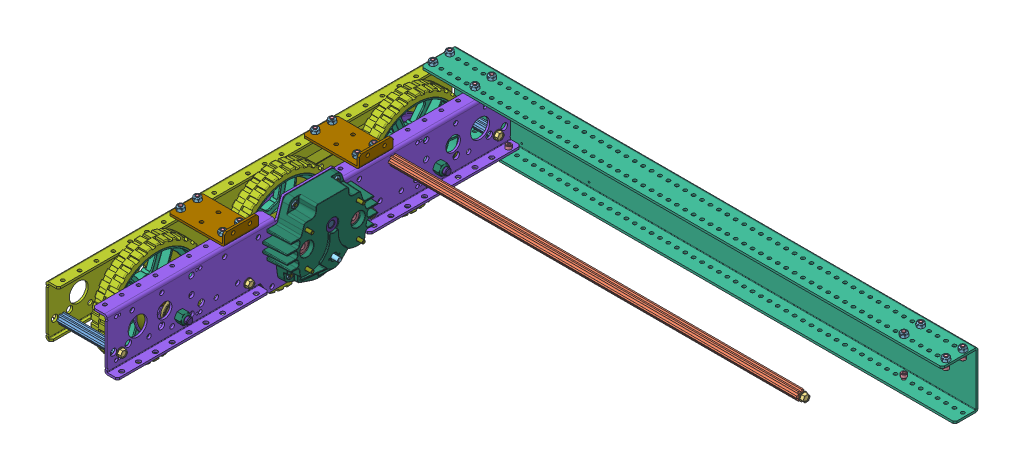
SolidWorks assembly AM14U3 Wide Half, configuration Default. Lengths in mm.
Overall size (799.92 215.23 613.54).
150 component instances, 35 part files, 25 mates.
Components (placement in the parent):
- AM14U3 Wide Frame Half-1: AM14U3 Wide Frame Half [Default] at (332.649 29.2384 -211.4076) size (799.34 116.33 613.54)
  - 500 Churro 3.375 in-1: 500 Churro 3.375 in [Default] at (-704.85 -61.341 539.242) x (0 0 1) z (-1 0 0) size (14.66 12.7 85.72)
  - 500 Churro 3.375 in-2: 500 Churro 3.375 in [Default] at (-704.85 -66.929 346.837) x (0 0 1) z (-1 0 0) size (14.66 12.7 85.72)
  - 500 Churro 3.375 in-3: 500 Churro 3.375 in [Default] at (-704.85 -66.929 162.687) x (0 0 1) z (-1 0 0) size (14.66 12.7 85.72)
  - 500 Churro 3.375 in-4: 500 Churro 3.375 in [Default] at (-790.575 -61.341 -29.718) x (0 0 -1) z (1 0 0) size (14.66 12.7 85.72)
  - 500 Churro 24.25 in-1: 500 Churro 24.25 in [Default] at (-85.725 -15.494 127.762) x (0 0 1) z (-1 0 0) size (14.66 12.7 615.95)
  - 0.25-20 x 0.75 in Thread Rolling Screw-1: 0.25-20 x 0.75 in Thread Rolling Screw [FHTS 0.25-20-G-0.75-C] at (-701.675 -61.341 539.242) x (-1 0 0) z (0 0.924225 0.381849) size (24.64 12.19 12.19)
  - 0.25-20 x 0.75 in Thread Rolling Screw-2: 0.25-20 x 0.75 in Thread Rolling Screw [FHTS 0.25-20-G-0.75-C] at (-701.675 -66.929 346.837) x (-1 0 0) z (0 0.924225 0.381849) size (24.64 12.19 12.19)
  - 0.25-20 x 0.75 in Thread Rolling Screw-3: 0.25-20 x 0.75 in Thread Rolling Screw [FHTS 0.25-20-G-0.75-C] at (-701.675 -66.929 162.687) x (-1 0 0) z (0 0.924225 0.381849) size (24.64 12.19 12.19)
  - 0.25-20 x 0.75 in Thread Rolling Screw-4: 0.25-20 x 0.75 in Thread Rolling Screw [FHTS 0.25-20-G-0.75-C] at (-701.675 -61.341 -29.718) x (-1 0 0) z (0 0.924225 0.381849) size (24.64 12.19 12.19)
  - 0.25-20 x 0.75 in Thread Rolling Screw-5: 0.25-20 x 0.75 in Thread Rolling Screw [FHTS 0.25-20-G-0.75-C] at (-793.75 -61.341 -29.718) size (24.64 12.19 12.19)
  - 0.25-20 x 0.75 in Thread Rolling Screw-6: 0.25-20 x 0.75 in Thread Rolling Screw [FHTS 0.25-20-G-0.75-C] at (-793.75 -66.929 162.687) size (24.64 12.19 12.19)
  - 0.25-20 x 0.75 in Thread Rolling Screw-7: 0.25-20 x 0.75 in Thread Rolling Screw [FHTS 0.25-20-G-0.75-C] at (-704.85 -15.494 127.762) size (24.64 12.19 12.19)
  - 0.25-20 x 0.75 in Thread Rolling Screw-8: 0.25-20 x 0.75 in Thread Rolling Screw [FHTS 0.25-20-G-0.75-C] at (-793.75 -66.929 346.837) size (24.64 12.19 12.19)
  - 0.25-20 x 0.75 in Thread Rolling Screw-9: 0.25-20 x 0.75 in Thread Rolling Screw [FHTS 0.25-20-G-0.75-C] at (-793.75 -61.341 539.242) size (24.64 12.19 12.19)
  - 0.25-20 x 0.75 in Thread Rolling Screw-10: 0.25-20 x 0.75 in Thread Rolling Screw [FHTS 0.25-20-G-0.75-C] at (-82.55 -15.494 127.762) x (-1 0 0) z (0 0.116139 -0.993233) size (24.64 12.19 12.19)
  - 10-32 x 0.5 in SHCS Screw-19: 10-32 x 0.5 in SHCS Screw [HX-SHCS 0.19-32x1.375x1-C] at (-781.05 -11.43 -37.338) x (0 1 0) z (0 0 1) size (17.53 7.94 7.94)
  - 10-32 x 0.5 in SHCS Screw-20: 10-32 x 0.5 in SHCS Screw [HX-SHCS 0.19-32x1.375x1-C] at (-781.05 -11.43 -11.938) x (0 1 0) z (0 0 1) size (17.53 7.94 7.94)
  - 10-32 x 0.5 in SHCS Screw-21: 10-32 x 0.5 in SHCS Screw [HX-SHCS 0.19-32x1.375x1-C] at (-717.55 -11.43 -37.338) x (0 1 0) z (0 0 1) size (17.53 7.94 7.94)
  - 10-32 x 0.5 in SHCS Screw-22: 10-32 x 0.5 in SHCS Screw [HX-SHCS 0.19-32x1.375x1-C] at (-717.55 -11.43 -11.938) x (0 1 0) z (0 0 1) size (17.53 7.94 7.94)
  - 10-32 x 0.5 in SHCS Screw-23: 10-32 x 0.5 in SHCS Screw [HX-SHCS 0.19-32x1.375x1-C] at (-781.05 -11.43 140.462) x (0 1 0) z (0 0 1) size (17.53 7.94 7.94)
  - 10-32 x 0.5 in SHCS Screw-24: 10-32 x 0.5 in SHCS Screw [HX-SHCS 0.19-32x1.375x1-C] at (-781.05 -11.43 165.862) x (0 1 0) z (0 0 1) size (17.53 7.94 7.94)
  - 10-32 x 0.5 in SHCS Screw-25: 10-32 x 0.5 in SHCS Screw [HX-SHCS 0.19-32x1.375x1-C] at (-717.55 -11.43 140.462) x (0 1 0) z (0 0 1) size (17.53 7.94 7.94)
  - 10-32 x 0.5 in SHCS Screw-26: 10-32 x 0.5 in SHCS Screw [HX-SHCS 0.19-32x1.375x1-C] at (-717.55 -11.43 165.862) x (0 1 0) z (0 0 1) size (17.53 7.94 7.94)
  - 10-32 x 0.5 in SHCS Screw-27: 10-32 x 0.5 in SHCS Screw [HX-SHCS 0.19-32x1.375x1-C] at (-781.05 -11.43 343.662) x (0 1 0) z (0 0 1) size (17.53 7.94 7.94)
  - 10-32 x 0.5 in SHCS Screw-28: 10-32 x 0.5 in SHCS Screw [HX-SHCS 0.19-32x1.375x1-C] at (-781.05 -11.43 369.062) x (0 1 0) z (0 0 1) size (17.53 7.94 7.94)
  - 10-32 x 0.5 in SHCS Screw-29: 10-32 x 0.5 in SHCS Screw [HX-SHCS 0.19-32x1.375x1-C] at (-717.55 -11.43 343.662) x (0 1 0) z (0 0 1) size (17.53 7.94 7.94)
  - 10-32 x 0.5 in SHCS Screw-30: 10-32 x 0.5 in SHCS Screw [HX-SHCS 0.19-32x1.375x1-C] at (-717.55 -11.43 369.062) x (0 1 0) z (0 0 1) size (17.53 7.94 7.94)
  - 10-32 x 0.5 in SHCS Screw-31: 10-32 x 0.5 in SHCS Screw [HX-SHCS 0.19-32x1.375x1-C] at (-692.15 -73.152 -37.338) x (0 -1 0) z (0 0 1) size (17.53 7.94 7.94)
  - 10-32 x 0.5 in SHCS Screw-32: 10-32 x 0.5 in SHCS Screw [HX-SHCS 0.19-32x1.375x1-C] at (-6.35 -11.176 -11.938) x (0 1 0) z (-0.461963 0 0.886899) size (17.53 7.94 7.94)
  - 10-32 x 0.5 in SHCS Screw-33: 10-32 x 0.5 in SHCS Screw [HX-SHCS 0.19-32x1.375x1-C] at (-6.35 -11.176 -37.338) x (0 1 0) z (0 0 1) size (17.53 7.94 7.94)
  - 10-32 x 0.5 in SHCS Screw-34: 10-32 x 0.5 in SHCS Screw [HX-SHCS 0.19-32x1.375x1-C] at (-69.85 -11.176 -11.938) x (0 1 0) z (0 0 1) size (17.53 7.94 7.94)
  - 10-32 x 0.5 in SHCS Screw-35: 10-32 x 0.5 in SHCS Screw [HX-SHCS 0.19-32x1.375x1-C] at (-69.85 -11.176 -37.338) x (0 1 0) z (0 0 1) size (17.53 7.94 7.94)
  - 10-32 x 0.5 in SHCS Screw-36: 10-32 x 0.5 in SHCS Screw [HX-SHCS 0.19-32x1.375x1-C] at (-95.25 -73.406 -37.338) x (0 -1 0) z (0.251234 0 0.967926) size (17.53 7.94 7.94)
  - 10-32 Nylock Nut-19: 10-32 Nylock Nut [Default] at (-717.55 0 -11.938) x (1 0 0) z (0 1 0) size (10.18 11.01 7.1)
  - 10-32 Nylock Nut-20: 10-32 Nylock Nut [Default] at (-717.55 0 -37.338) x (1 0 0) z (0 1 0) size (10.18 11.01 7.1)
  - 10-32 Nylock Nut-21: 10-32 Nylock Nut [Default] at (-781.05 0 -11.938) x (1 0 0) z (0 1 0) size (10.18 11.01 7.1)
  - 10-32 Nylock Nut-22: 10-32 Nylock Nut [Default] at (-781.05 0 -37.338) x (1 0 0) z (0 1 0) size (10.18 11.01 7.1)
  - 10-32 Nylock Nut-23: 10-32 Nylock Nut [Default] at (-781.05 -0.254 140.462) x (1 0 0) z (0 1 0) size (10.18 11.01 7.1)
  - 10-32 Nylock Nut-24: 10-32 Nylock Nut [Default] at (-781.05 -0.254 165.862) x (1 0 0) z (0 1 0) size (10.18 11.01 7.1)
  - 10-32 Nylock Nut-25: 10-32 Nylock Nut [Default] at (-717.55 -0.254 140.462) x (1 0 0) z (0 1 0) size (10.18 11.01 7.1)
  - 10-32 Nylock Nut-26: 10-32 Nylock Nut [Default] at (-717.55 -0.254 165.862) x (1 0 0) z (0 1 0) size (10.18 11.01 7.1)
  - 10-32 Nylock Nut-27: 10-32 Nylock Nut [Default] at (-781.05 -0.254 343.662) x (1 0 0) z (0 1 0) size (10.18 11.01 7.1)
  - 10-32 Nylock Nut-28: 10-32 Nylock Nut [Default] at (-781.05 -0.254 369.062) x (1 0 0) z (0 1 0) size (10.18 11.01 7.1)
  - 10-32 Nylock Nut-29: 10-32 Nylock Nut [Default] at (-717.55 -0.254 343.662) x (1 0 0) z (0 1 0) size (10.18 11.01 7.1)
  - 10-32 Nylock Nut-30: 10-32 Nylock Nut [Default] at (-717.55 -0.254 369.062) x (1 0 0) z (0 1 0) size (10.18 11.01 7.1)
  - 10-32 Nylock Nut-31: 10-32 Nylock Nut [Default] at (-692.15 -84.582 -37.338) x (1 0 0) z (0 -1 0) size (10.18 11.01 7.1)
  - 10-32 Nylock Nut-32: 10-32 Nylock Nut [Default] at (-95.25 -84.582 -37.338) x (1 0 0) z (0 -1 0) size (10.18 11.01 7.1)
  - 10-32 Nylock Nut-33: 10-32 Nylock Nut [Default] at (-69.85 0 -11.938) x (1 0 0) z (0 1 0) size (10.18 11.01 7.1)
  - 10-32 Nylock Nut-34: 10-32 Nylock Nut [Default] at (-69.85 0 -37.338) x (1 0 0) z (0 1 0) size (10.18 11.01 7.1)
  - 10-32 Nylock Nut-35: 10-32 Nylock Nut [Default] at (-6.35 0 -37.338) x (1 0 0) z (0 1 0) size (10.18 11.01 7.1)
  - 10-32 Nylock Nut-36: 10-32 Nylock Nut [Default] at (-6.35 0 -11.938) x (1 0 0) z (0 1 0) size (10.18 11.01 7.1)
  - AM14U3 End Plate-1: AM14U3 End Plate [Default] at (-787.4 -81.407 -53.975) x (1 0 0) z (0 -1 0) size (787.4 53.98 84.58)
  - AM14U3 Outer Plate_Wide-1: AM14U3 Outer Plate_Wide [Default] at (-769.3485 -27.0221 -29.1885) x (0 0 1) z (0 -1 0) size (609.6 19.05 77.72)
  - AM14U3 Inner Plate_Wide-1: AM14U3 Inner Plate_Wide [Default] at (-713.7116 -19.2169 539.8409) x (0 0 -1) z (0 -1 0) size (609.6 38.1 116.33)
  - Bracket 2x3 Hole Pattern-1: Bracket 2x3 Hole Pattern [Default] at (-787.4 -3.429 394.462) size (85.72 19.05 50.8)
  - Bracket 2x3 Hole Pattern-2: Bracket 2x3 Hole Pattern [Default] at (-787.4 -3.429 191.262) size (85.72 19.05 50.8)
- Toughbox Mini Kit 1 - Yellow-1: Toughbox Mini Kit 1 - Yellow [Default] at (-419.5676 -40.7756 134.4552) x (0 0.001296 0.999999) z (-1 0 0) size (140.05 131.97 142.29)
  - TB Mini Small Hex Shaft-1: TB Mini Small Hex Shaft [Default] at (-128.9299 31.4042 -52.3959) x (-0.63944 -0.768841 0) z (-0.768841 0.63944 0) size (11 38.23 9.52)
  - Large Cluster Gear Hex 50t 0.375 in-1: Large Cluster Gear Hex 50t 0.375 in [Default] at (-91.0349 50.9043 -67.5597) x (-0.63944 -0.768841 0) z (0 0 -1) size (65.97 66.04 10.16)
  - Bearing FR6ZZ-1: Bearing FR6ZZ [Default] at (-96.247 60.278 -52.5991) x (-0.893862 0.448342 0) z (0 0 1) size (24.69 24.69 7.16)
  - 10-32 Nylock Nut-1: 10-32 Nylock Nut [Default] at (-129.8464 -8.0737 -56.3837) x (0.501678 0.865055 0) z (0 0 -1) size (10.18 11.01 7.1)
  - 10-32 Nylock Nut-2: 10-32 Nylock Nut [Default] at (-59.2462 80.7349 -56.3837) x (0.999999 -0.001296 0) z (0 0 -1) size (10.18 11.01 7.1)
  - 10-32 Nylock Nut-3: 10-32 Nylock Nut [Default] at (-122.7461 80.8172 -56.3837) x (0.500567 0.865698 0) z (0 0 -1) size (10.18 11.01 7.1)
  - 10-32 Nylock Nut-4: 10-32 Nylock Nut [Default] at (-52.3764 -8.1741 -56.3837) x (-0.501678 -0.865055 0) z (0 0 -1) size (10.18 11.01 7.1)
  - Washer 5-16 in-1: Washer 5-16 in [Default] at (-52.3162 38.3079 -77.7705) x (-0.418041 0.908428 0) z (0 0 -1) size (17.53 17.53 1.47)
  - Washer 5-16 in-2: Washer 5-16 in [Default] at (-52.3162 38.3079 -76.2973) x (0.897267 -0.441488 0) z (0 0 -1) size (17.53 17.53 1.47)
  - Washer 5-16 in-3: Washer 5-16 in [Default] at (-129.7861 38.4083 -77.7705) x (-0.990116 0.140253 0) z (0 0 1) size (17.53 17.53 1.47)
  - Washer 5-16 in-4: Washer 5-16 in [Default] at (-129.7861 38.4083 -79.2437) x (-0.681761 0.731575 0) z (0 0 1) size (17.53 17.53 1.47)
  - CIM Gear 14t 8 mm-1: CIM Gear 14t 8 mm [Default] at (-52.3162 38.3079 -63.5973) x (0.081921 0.996639 0) z (0 0 -1) size (20.03 20.32 12.7)
  - CIM Gear 14t 8 mm-2: CIM Gear 14t 8 mm [Default] at (-129.7861 38.4083 -63.5973) x (0.725998 0.687697 0) z (0 0 -1) size (20.03 20.32 12.7)
  - TB Mini Housing-1: TB Mini Housing [Default] at (-91.0876 10.1882 -86.3557) x (0.999999 -0.001296 0) z (0 0 1) size (139.9 118.55 41.54)
  - 10-32 x 0.625 in SHCS Screw-1: 10-32 x 0.625 in SHCS Screw [Default] at (-52.2832 63.7078 -74.4685) x (-0.564778 -0.825243 0) z (-0.825243 0.564778 0) size (7.82 20.65 7.82)
  - 10-32 x 0.625 in SHCS Screw-2: 10-32 x 0.625 in SHCS Screw [Default] at (-122.7461 80.8172 -42.5915) x (0.507484 -0.861661 0) z (-0.861661 -0.507484 0) size (7.82 20.65 7.82)
  - 10-32 x 0.625 in SHCS Screw-3: 10-32 x 0.625 in SHCS Screw [Default] at (-52.3764 -8.1741 -42.5915) x (0.507484 -0.861661 0) z (-0.861661 -0.507484 0) size (7.82 20.65 7.82)
  - 10-32 x 0.625 in SHCS Screw-4: 10-32 x 0.625 in SHCS Screw [Default] at (-129.8464 -8.0737 -42.5915) x (0.507484 -0.861661 0) z (-0.861661 -0.507484 0) size (7.82 20.65 7.82)
  - 10-32 x 0.625 in SHCS Screw-5: 10-32 x 0.625 in SHCS Screw [Default] at (-59.2462 80.7349 -42.5915) x (0.740711 -0.671824 0) z (-0.671824 -0.740711 0) size (7.82 20.65 7.82)
  - 10-32 x 0.625 in SHCS Screw-6: 10-32 x 0.625 in SHCS Screw [Default] at (-52.3491 12.9079 -74.4685) x (-0.564778 -0.825243 0) z (-0.825243 0.564778 0) size (7.82 20.65 7.82)
  - 10-32 x 0.625 in SHCS Screw-7: 10-32 x 0.625 in SHCS Screw [Default] at (-129.7532 63.8083 -74.4685) x (-0.966277 -0.257503 0) z (-0.257503 0.966277 0) size (7.82 20.65 7.82)
  - 10-32 x 0.625 in SHCS Screw-8: 10-32 x 0.625 in SHCS Screw [Default] at (-129.819 13.0083 -74.4685) x (-0.99652 0.083357 0) z (0.083357 0.99652 0) size (7.82 20.65 7.82)
  - Bearing R6ZZ-3: Bearing R6ZZ [Default] at (-91.0349 50.9043 -84.8317) x (0.958138 -0.286306 0) z (0 0 1) size (22.23 22.23 7.11)
  - Bearing R6ZZ-4: Bearing R6ZZ [Default] at (-91.0876 10.1882 -84.8317) x (-0.661529 0.74992 0) z (0 0 1) size (22.23 22.23 7.11)
  - Retaining Clip 8 mm-1: Retaining Clip 8 mm [Default] at (-129.7861 38.4083 -63.5973) x (0 0 1) z (-1 0 0) size (1.09 14.83 14.83)
  - Retaining Clip 8 mm-2: Retaining Clip 8 mm [Default] at (-52.3162 38.3079 -63.5973) x (0 0 1) z (-1 0 0) size (1.09 14.83 14.83)
  - External Klipring 0.5 in-1: External Klipring 0.5 in [Default] at (-91.0876 10.1882 -64.4355) x (0.996411 -0.084651 0) z (0 0 1) size (19.07 20.96 1.27)
  - Hex Bearing FR8ZZ-1: Hex Bearing FR8ZZ [Default] at (-91.0876 10.1882 -44.6717) x (0.206517 -0.978443 0) z (0 0 -1) size (31.12 31.12 7.93)
  - Small Cluster Gear Hex 16t 0.375 in-1: Small Cluster Gear Hex 16t 0.375 in [Default] at (-91.0349 50.9043 -67.5597) x (0 0 1) z (0.346116 -0.938192 0) size (15.19 22.57 22.57)
  - Large Output Gear Hex 48t 0.5 in-1: Large Output Gear Hex 48t 0.5 in [Default] at (-91.0876 10.1882 -63.1655) x (0 0 1) z (0.744098 0.668071 0) size (10.21 63.42 63.42)
  - TB Mini Hex Output Shaft-2: TB Mini Hex Output Shaft [Default] at (-99.4862 -30.7356 -52.3197) x (0.206517 -0.978443 0) z (-0.978443 -0.206517 0) size (14.66 142.29 12.7)
- Hex Bearing FR8ZZ-1: Hex Bearing FR8ZZ [Default] at (-464.3293 -30.7056 43.3544) x (0 0.309139 -0.951017) z (1 0 0) size (31.12 31.12 7.93)
- Wheel HiGrip 6 in - Hub, Double Pulley-1: Wheel HiGrip 6 in - Hub, Double Pulley [Default] at (-383.2007 0.7296 193.1607) x (-1 0 0) z (0 -0.669035 -0.743231) size (81.42 152.4 152.4)
  - Wheel HiGrip 6 in-1: Wheel HiGrip 6 in [Default] at (83.7987 67.439 110.9939) size (35.05 152.4 152.4)
    - Wheel HiGrip 6 in_Wheel-1: Wheel HiGrip 6 in_Wheel [Default] at (-52.6446 9.4231 21.378) size (35.05 132.08 132.08)
    - Wheel HiGrip 6 in_Tread-1: Wheel HiGrip 6 in_Tread [Default] at (-65.3446 9.4231 21.378) x (0 0 -1) z (1 0 0) size (152.4 152.4 25.58)
  - Half Pulley 42t 5 mm HTD-1: Half Pulley 42t 5 mm HTD [Default] at (47.6006 76.862 132.3719) x (1 0 0) z (0 -0.5 0.866025) size (13 74.23 74.23)
  - Half Pulley 42t 5 mm HTD-2: Half Pulley 42t 5 mm HTD [Default] at (64.263 76.862 132.3719) x (-1 0 0) z (0 -0.499927 0.866067) size (13 74.23 74.23)
  - 10-24 x 1.25 in Thread Forming Screw-1: 10-24 x 1.25 in Thread Forming Screw [93882A213] at (63.247 76.8605 108.5602) x (0 0 -1) z (1 0 0) size (10.52 10.52 35.59)
  - 10-24 x 1.25 in Thread Forming Screw-2: 10-24 x 1.25 in Thread Forming Screw [93882A213] at (63.247 97.4833 120.4656) x (0 0 -1) z (1 0 0) size (10.52 10.52 35.59)
  - 10-24 x 1.25 in Thread Forming Screw-3: 10-24 x 1.25 in Thread Forming Screw [93882A213] at (63.247 56.2398 144.2799) x (0 0 -1) z (1 0 0) size (10.52 10.52 35.59)
  - 10-24 x 1.25 in Thread Forming Screw-4: 10-24 x 1.25 in Thread Forming Screw [93882A213] at (63.247 76.8625 156.1852) x (0 -0.95788 -0.287168) z (1 0 0) size (10.52 10.52 35.59)
  - 10-24 x 1.25 in Thread Forming Screw-5: 10-24 x 1.25 in Thread Forming Screw [93882A213] at (63.247 97.4843 144.2781) x (0 -0.868976 0.494854) z (1 0 0) size (10.52 10.52 35.59)
  - 10-24 x 1.25 in Thread Forming Screw-6: 10-24 x 1.25 in Thread Forming Screw [93882A213] at (63.247 56.2388 120.4674) x (0 -0.748729 -0.662876) z (1 0 0) size (10.52 10.52 35.59)
  - Half Pulley 42t 5 mm HTD-3: Half Pulley 42t 5 mm HTD [Default] at (-1.9548 76.8628 132.3714) x (1 0 0) z (0 -1 -0.000063) size (13 74.23 74.23)
  - Half Pulley 42t 5 mm HTD-4: Half Pulley 42t 5 mm HTD [Default] at (14.7076 76.8628 132.3714) x (-1 0 0) z (0 -1 0.000021) size (13 74.23 74.23)
  - Hex Hub 500 EX-1: Hex Hub 500 EX [Default] at (-8.3048 76.8628 132.3714) x (0 -0.866025 -0.5) z (0 -0.5 0.866025) size (55.37 25.4 51.33)
  - 10-24 x 1.25 in Thread Forming Screw-7: 10-24 x 1.25 in Thread Forming Screw [93882A213] at (-5.2568 97.485 120.4652) x (0 0 1) z (-1 0 0) size (10.52 10.52 35.59)
  - 10-24 x 1.25 in Thread Forming Screw-8: 10-24 x 1.25 in Thread Forming Screw [93882A213] at (-5.2568 76.8628 108.5589) x (0 0 1) z (-1 0 0) size (10.52 10.52 35.59)
  - 10-24 x 1.25 in Thread Forming Screw-9: 10-24 x 1.25 in Thread Forming Screw [93882A213] at (-5.2568 56.2406 120.4652) x (0 0 1) z (-1 0 0) size (10.52 10.52 35.59)
  - 10-24 x 1.25 in Thread Forming Screw-10: 10-24 x 1.25 in Thread Forming Screw [93882A213] at (-5.2568 97.485 144.2777) x (0 -0.99374 -0.111715) z (-1 0 0) size (10.52 10.52 35.59)
  - 10-24 x 1.25 in Thread Forming Screw-11: 10-24 x 1.25 in Thread Forming Screw [93882A213] at (-5.2568 56.2406 144.2777) x (0 -0.138911 0.990305) z (-1 0 0) size (10.52 10.52 35.59)
  - 10-24 x 1.25 in Thread Forming Screw-12: 10-24 x 1.25 in Thread Forming Screw [93882A213] at (-5.2568 76.8628 156.1839) x (0 -0.98811 -0.15375) z (-1 0 0) size (10.52 10.52 35.59)
  - Hex Spacer 0.57 in x 0.5 ID-1: Hex Spacer 0.57 in x 0.5 ID [Default] at (57.8495 76.862 132.3719) x (0 -0.866025 -0.5) z (0 -0.5 0.866025) size (28.55 14.48 28.55)
- Wheel HiGrip 6 in - Bearings, Pulleys, Spacers-1: Wheel HiGrip 6 in - Bearings, Pulleys, Spacers [Default] at (-446.6875 -83.827 95.5079) x (1 0 0) z (0 -0.158569 0.987348) size (85.56 152.4 152.4)
  - Wheel HiGrip 6 in-1: Wheel HiGrip 6 in [Default] at (83.7987 67.439 110.9939) size (35.05 152.4 152.4)
    - Wheel HiGrip 6 in_Wheel-1: Wheel HiGrip 6 in_Wheel [Default] at (-52.6446 9.4231 21.378) size (35.05 132.08 132.08)
    - Wheel HiGrip 6 in_Tread-1: Wheel HiGrip 6 in_Tread [Default] at (-65.3446 9.4231 21.378) x (0 0 -1) z (1 0 0) size (152.4 152.4 25.58)
  - Half Pulley 42t 5 mm HTD-1: Half Pulley 42t 5 mm HTD [Default] at (47.6006 76.862 132.3719) x (1 0 0) z (0 -0.5 0.866025) size (13 74.23 74.23)
  - Half Pulley 42t 5 mm HTD-2: Half Pulley 42t 5 mm HTD [Default] at (64.263 76.862 132.3719) x (-1 0 0) z (0 -0.499927 0.866067) size (13 74.23 74.23)
  - Bearing 1614ZZ-1: Bearing 1614ZZ [Default] at (62.612 76.862 132.3719) x (0 -0.157148 -0.987575) z (-1 0 0) size (28.57 28.57 9.53)
  - Bearing 1614ZZ-2: Bearing 1614ZZ [Default] at (15.2791 76.862 132.3719) x (0 0 -1) z (1 0 0) size (28.57 28.57 9.53)
  - 10-24 x 1.25 in Thread Forming Screw-1: 10-24 x 1.25 in Thread Forming Screw [93882A213] at (63.247 76.8605 108.5602) x (0 0 -1) z (1 0 0) size (10.52 10.52 35.59)
  - 10-24 x 1.25 in Thread Forming Screw-2: 10-24 x 1.25 in Thread Forming Screw [93882A213] at (63.247 97.4833 120.4656) x (0 0 -1) z (1 0 0) size (10.52 10.52 35.59)
  - 10-24 x 1.25 in Thread Forming Screw-3: 10-24 x 1.25 in Thread Forming Screw [93882A213] at (63.247 56.2398 144.2799) x (0 0 -1) z (1 0 0) size (10.52 10.52 35.59)
  - 10-24 x 1.25 in Thread Forming Screw-4: 10-24 x 1.25 in Thread Forming Screw [93882A213] at (63.247 76.8625 156.1852) x (0 -0.95788 -0.287168) z (1 0 0) size (10.52 10.52 35.59)
  - 10-24 x 1.25 in Thread Forming Screw-5: 10-24 x 1.25 in Thread Forming Screw [93882A213] at (63.247 97.4843 144.2781) x (0 -0.868976 0.494854) z (1 0 0) size (10.52 10.52 35.59)
  - 10-24 x 1.25 in Thread Forming Screw-6: 10-24 x 1.25 in Thread Forming Screw [93882A213] at (63.247 56.2388 120.4674) x (0 -0.977348 -0.211637) z (1 0 0) size (10.52 10.52 35.59)
  - Spacer 0.28 in x 0.382 ID-1: Spacer 0.28 in x 0.382 ID [Default] at (74.4865 76.862 132.3719) x (0 -0.35357 0.935408) z (-1 0 0) size (13.16 13.16 7.11)
  - Spacer 0.85 in x 0.38 ID-1: Spacer 0.85 in x 0.38 ID [Default] at (-11.0734 76.862 132.3719) x (0 0 -1) z (1 0 0) size (19.05 19.05 21.59)
- Wheel HiGrip 6 in - Bearings, Pulleys, Spacers-2: Wheel HiGrip 6 in - Bearings, Pulleys, Spacers [Default] at (-383.2744 64.0641 -30.1002) x (-1 0 0) z (0 -0.924225 -0.381849) size (85.56 152.4 152.4)
  - Wheel HiGrip 6 in-1: Wheel HiGrip 6 in [Default] at (83.7987 67.439 110.9939) size (35.05 152.4 152.4)
    - Wheel HiGrip 6 in_Wheel-1: Wheel HiGrip 6 in_Wheel [Default] at (-52.6446 9.4231 21.378) size (35.05 132.08 132.08)
    - Wheel HiGrip 6 in_Tread-1: Wheel HiGrip 6 in_Tread [Default] at (-65.3446 9.4231 21.378) x (0 0 -1) z (1 0 0) size (152.4 152.4 25.58)
  - Half Pulley 42t 5 mm HTD-1: Half Pulley 42t 5 mm HTD [Default] at (47.6006 76.862 132.3719) x (1 0 0) z (0 -0.5 0.866025) size (13 74.23 74.23)
  - Half Pulley 42t 5 mm HTD-2: Half Pulley 42t 5 mm HTD [Default] at (64.263 76.862 132.3719) x (-1 0 0) z (0 -0.499927 0.866067) size (13 74.23 74.23)
  - Bearing 1614ZZ-1: Bearing 1614ZZ [Default] at (62.612 76.862 132.3719) x (0 -0.157148 -0.987575) z (-1 0 0) size (28.57 28.57 9.53)
  - Bearing 1614ZZ-2: Bearing 1614ZZ [Default] at (15.2791 76.862 132.3719) x (0 0 -1) z (1 0 0) size (28.57 28.57 9.53)
  - 10-24 x 1.25 in Thread Forming Screw-1: 10-24 x 1.25 in Thread Forming Screw [93882A213] at (63.247 76.8605 108.5602) x (0 0 -1) z (1 0 0) size (10.52 10.52 35.59)
  - 10-24 x 1.25 in Thread Forming Screw-2: 10-24 x 1.25 in Thread Forming Screw [93882A213] at (63.247 97.4833 120.4656) x (0 0 -1) z (1 0 0) size (10.52 10.52 35.59)
  - 10-24 x 1.25 in Thread Forming Screw-3: 10-24 x 1.25 in Thread Forming Screw [93882A213] at (63.247 56.2398 144.2799) x (0 0 -1) z (1 0 0) size (10.52 10.52 35.59)
  - 10-24 x 1.25 in Thread Forming Screw-4: 10-24 x 1.25 in Thread Forming Screw [93882A213] at (63.247 76.8625 156.1852) x (0 -0.95788 -0.287168) z (1 0 0) size (10.52 10.52 35.59)
  - 10-24 x 1.25 in Thread Forming Screw-5: 10-24 x 1.25 in Thread Forming Screw [93882A213] at (63.247 97.4843 144.2781) x (0 -0.868976 0.494854) z (1 0 0) size (10.52 10.52 35.59)
  - 10-24 x 1.25 in Thread Forming Screw-6: 10-24 x 1.25 in Thread Forming Screw [93882A213] at (63.247 56.2388 120.4674) x (0 -0.977348 -0.211637) z (1 0 0) size (10.52 10.52 35.59)
  - Spacer 0.28 in x 0.382 ID-1: Spacer 0.28 in x 0.382 ID [Default] at (74.4865 76.862 132.3719) x (0 -0.35357 0.935408) z (-1 0 0) size (13.16 13.16 7.11)
  - Spacer 0.85 in x 0.38 ID-1: Spacer 0.85 in x 0.38 ID [Default] at (-11.0734 76.862 132.3719) x (0 0 -1) z (1 0 0) size (19.05 19.05 21.59)
- 0.375-16 Nylock Nut-1: 0.375-16 Nylock Nut [91831A127] at (-369.026 -28.9276 238.3929) x (0 -1 0) z (0 0 1) size (14.29 12 16.5)
- 0.375-16 Nylock Nut-2: 0.375-16 Nylock Nut [91831A127] at (-369.026 -28.9276 -151.6841) x (0 -1 0) z (0 0 1) size (14.29 12 16.5)
- Timing Belt HTD 15 mm_Wide-1: Timing Belt HTD 15 mm_Wide [Default] at (-384.0869 -30.7056 43.3544) x (0 0.009116 0.999958) z (-1 0 0) size (264.24 69.19 15)
- Timing Belt HTD 15 mm_Wide-2: Timing Belt HTD 15 mm_Wide [Default] at (-445.875 -30.7056 43.3544) x (0 0.009116 -0.999958) z (1 0 0) size (264.24 69.19 15)
- 0.375-16 x 4.25 in HHS Bolt-1: 0.375-16 x 4.25 in HHS Bolt [HFBOLT 0.375-16x2.5x1-C] at (-467.2732 -28.9276 238.3929) x (1 0 0) z (0 -0.996292 -0.086036) size (114.12 16.48 14.27)
- 0.375-16 x 4.25 in HHS Bolt-2: 0.375-16 x 4.25 in HHS Bolt [HFBOLT 0.375-16x2.5x1-C] at (-467.2732 -28.9276 -151.6841) size (114.12 16.48 14.27)
Mates (geometry in assembly coordinates):
- Concentric1: concentric anti-aligned: cylinder of AM14U3 Wide Frame Half-1/AM14U3 Inner Plate_Wide-1 through (-372.201 -30.7056 43.3544) axis (1 0 0) radius 14.2875; cylinder of Toughbox Mini Kit 1 - Yellow-1/Hex Bearing FR8ZZ-1 through (-366.9686 -30.7056 43.3544) axis (-1 0 0) radius 14.2875
- Parallel1: parallel: plane of AM14U3 Wide Frame Half-1/AM14U3 Inner Plate_Wide-1 through (-369.026 49.3044 -4.2706) normal (0 1 0); line of Toughbox Mini Kit 1 - Yellow-1/TB Mini Housing-1 through (-368.5002 48.8617 11.6044) axis (0 0 1)
- Coincident2: coincident anti-aligned: plane of AM14U3 Wide Frame Half-1/AM14U3 Inner Plate_Wide-1 through (-369.026 21.8724 449.7544) normal (1 0 0); plane of Toughbox Mini Kit 1 - Yellow-1/TB Mini Housing-1 through (-369.026 -30.7056 43.3544) normal (-1 0 0)
- Concentric21: concentric aligned: cylinder of AM14U3 Wide Frame Half-1/AM14U3 Outer Plate_Wide-1 through (-457.926 -30.7056 43.3544) axis (-1 0 0) radius 14.2875; cylinder of Hex Bearing FR8ZZ-1 through (-456.402 -30.7056 43.3544) axis (-1 0 0) radius 13.97
- Coincident31: coincident anti-aligned: plane of AM14U3 Wide Frame Half-1/AM14U3 Outer Plate_Wide-1 through (-457.926 21.8724 -363.0456) normal (1 0 0); plane of Hex Bearing FR8ZZ-1 through (-457.926 -26.3869 30.0687) normal (-1 0 0)
- Coincident4: coincident anti-aligned: plane of Toughbox Mini Kit 1 - Yellow-1/TB Mini Hex Output Shaft-2 through (-341.848 -23.5332 41.8309) normal (0 0.743231 -0.669035); plane of Hex Bearing FR8ZZ-1 through (-456.402 -23.5332 41.8309) normal (0 -0.743231 0.669035)
- Concentric3: concentric anti-aligned: cylinder of Toughbox Mini Kit 1 - Yellow-1/Hex Bearing FR8ZZ-1 through (-366.9686 -30.7056 43.3544) axis (-1 0 0) radius 14.2875; cylinder of Wheel HiGrip 6 in - Hub, Double Pulley-1/Hex Spacer 0.57 in x 0.5 ID-1 through (-455.5282 -30.7056 43.3544) axis (1 0 0) radius 14.2748
- Parallel2: parallel anti-aligned: plane of Toughbox Mini Kit 1 - Yellow-1/TB Mini Hex Output Shaft-2 through (-341.848 -23.5332 41.8309) normal (0 0.743231 -0.669035); plane of Wheel HiGrip 6 in - Hub, Double Pulley-1/Hex Hub 500 EX-1 through (-374.8959 -23.5181 41.8276) normal (0 -0.743231 0.669035)
- Coincident6: coincident anti-aligned: plane of Toughbox Mini Kit 1 - Yellow-1/Hex Bearing FR8ZZ-1 through (-374.8959 -30.7056 43.3544) normal (-1 0 0); plane of Wheel HiGrip 6 in - Hub, Double Pulley-1/Hex Hub 500 EX-1 through (-374.8959 -30.7047 43.3543) normal (1 0 0)
- Concentric4: concentric aligned: cylinder of AM14U3 Wide Frame Half-1/AM14U3 Inner Plate_Wide-1 through (-391.251 -28.9276 238.3929) axis (1 0 0) radius 4.826; cylinder of Wheel HiGrip 6 in - Bearings, Pulleys, Spacers-1/Spacer 0.28 in x 0.382 ID-1 through (-379.313 -28.9276 238.3929) axis (1 0 0) radius 6.5786
- Coincident7: coincident anti-aligned: plane of AM14U3 Wide Frame Half-1/AM14U3 Inner Plate_Wide-1 through (-372.201 21.8724 449.7544) normal (-1 0 0); plane of Wheel HiGrip 6 in - Bearings, Pulleys, Spacers-1/Spacer 0.28 in x 0.382 ID-1 through (-372.201 -28.9276 238.3929) normal (1 0 0)
- Concentric5: concentric anti-aligned: cylinder of AM14U3 Wide Frame Half-1/AM14U3 Inner Plate_Wide-1 through (-391.251 -28.9276 -151.6841) axis (1 0 0) radius 4.826; cylinder of Wheel HiGrip 6 in - Bearings, Pulleys, Spacers-2/Spacer 0.28 in x 0.382 ID-1 through (-450.6489 -28.9276 -151.6841) axis (-1 0 0) radius 6.5786
- Coincident8: coincident anti-aligned: plane of AM14U3 Wide Frame Half-1/AM14U3 Inner Plate_Wide-1 through (-372.201 21.8724 449.7544) normal (-1 0 0); plane of Wheel HiGrip 6 in - Bearings, Pulleys, Spacers-2/Spacer 0.85 in x 0.38 ID-1 through (-372.201 -28.9276 -151.6841) normal (1 0 0)
- Coincident11: coincident anti-aligned: plane of AM14U3 Wide Frame Half-1/AM14U3 Inner Plate_Wide-1 through (-369.026 21.8724 449.7544) normal (1 0 0); plane of 0.375-16 Nylock Nut-2 through (-369.026 -21.7838 -164.0574) normal (-1 0 0)
- Coincident12: coincident anti-aligned: plane of AM14U3 Wide Frame Half-1/AM14U3 Inner Plate_Wide-1 through (-369.026 21.8724 449.7544) normal (1 0 0); plane of 0.375-16 Nylock Nut-1 through (-369.026 -21.7838 226.0196) normal (-1 0 0)
- Concentric10: concentric anti-aligned: cylinder of Wheel HiGrip 6 in - Bearings, Pulleys, Spacers-1/Spacer 0.85 in x 0.38 ID-1 through (-436.1709 -28.9276 238.3929) axis (-1 0 0) radius 9.525; cylinder of Timing Belt HTD 15 mm_Wide-1 through (-399.0869 -28.9276 238.3929) axis (1 0 0) radius 33.4264
- Concentric11: concentric anti-aligned: cylinder of Hex Bearing FR8ZZ-1 through (-456.402 -30.7056 43.3544) axis (-1 0 0) radius 14.2875; cylinder of Timing Belt HTD 15 mm_Wide-1 through (-399.0869 -30.7056 43.3544) axis (1 0 0) radius 33.4264
- Coincident13: coincident anti-aligned: plane of Wheel HiGrip 6 in - Bearings, Pulleys, Spacers-1/Half Pulley 42t 5 mm HTD-1 through (-399.0869 -28.9276 238.3929) normal (1 0 0); plane of Timing Belt HTD 15 mm_Wide-1 through (-399.0869 -30.7056 43.3544) normal (-1 0 0)
- Concentric12: concentric anti-aligned: cylinder of Wheel HiGrip 6 in - Bearings, Pulleys, Spacers-2/Spacer 0.85 in x 0.38 ID-1 through (-393.791 -28.9276 -151.6841) axis (1 0 0) radius 9.525; cylinder of Timing Belt HTD 15 mm_Wide-2 through (-430.875 -28.9276 -151.6841) axis (-1 0 0) radius 33.4264
- Concentric13: concentric anti-aligned: circle of Hex Bearing FR8ZZ-1; cylinder of Timing Belt HTD 15 mm_Wide-2 through (-430.875 -30.7056 43.3544) axis (-1 0 0) radius 33.4264
- Coincident14: coincident anti-aligned: plane of Wheel HiGrip 6 in - Bearings, Pulleys, Spacers-2/Half Pulley 42t 5 mm HTD-1 through (-430.875 -28.9276 -151.6841) normal (-1 0 0); plane of Timing Belt HTD 15 mm_Wide-2 through (-430.875 -30.7056 43.3544) normal (1 0 0)
- Concentric72: concentric aligned: cylinder of AM14U3 Wide Frame Half-1/AM14U3 Outer Plate_Wide-1 through (-349.975 -28.9276 238.3929) axis (-1 0 0) radius 4.826; cylinder of 0.375-16 x 4.25 in HHS Bolt-1 through (-467.2732 -28.9276 238.3929) axis (-1 0 0) radius 4.7625
- Coincident102: coincident anti-aligned: plane of AM14U3 Wide Frame Half-1/AM14U3 Outer Plate_Wide-1 through (-461.101 21.8724 -363.0456) normal (-1 0 0); plane of 0.375-16 x 4.25 in HHS Bolt-1 through (-461.101 -29.6366 246.6039) normal (1 0 0)
- Concentric731: concentric aligned: cylinder of AM14U3 Wide Frame Half-1/AM14U3 Outer Plate_Wide-1 through (-349.975 -28.9276 -151.6841) axis (-1 0 0) radius 4.826; cylinder of 0.375-16 x 4.25 in HHS Bolt-2 through (-467.2732 -28.9276 -151.6841) axis (-1 0 0) radius 7.1374
- Coincident1031: coincident anti-aligned: plane of AM14U3 Wide Frame Half-1/AM14U3 Outer Plate_Wide-1 through (-461.101 21.8724 -363.0456) normal (-1 0 0); plane of 0.375-16 x 4.25 in HHS Bolt-2 through (-461.101 -20.686 -151.6841) normal (1 0 0)
